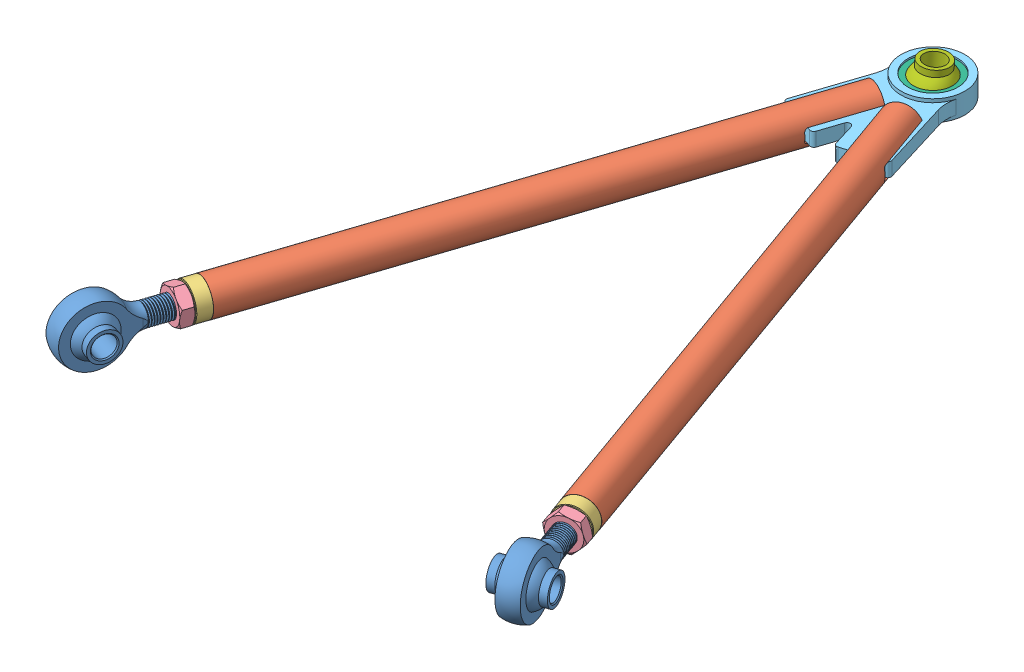
SolidWorks assembly SP-AB- Front Upper A-Arms, configuration Default. Lengths in mm.
Overall size (231.22 28.57 327.82).
12 component instances, 7 part files, 34 mates.
Components (placement in the parent):
- 6960T231_Super-Swivel Ball Joint Rod End-5: 6960T231_Super-Swivel Ball Joint Rod End [6960T231] at (-98.283 0 -18.0857) x (0 1 0) z (0.949383 0 0.314122) size (28.57 68.61 22.23)
- 6960T231_Super-Swivel Ball Joint Rod End-6: 6960T231_Super-Swivel Ball Joint Rod End [6960T231] at (90.2428 0 -17.9412) x (0 1 0) z (0.941797 0 -0.336181) size (28.57 68.61 22.23)
- SP-FR Upper A-Arm Tube-3: SP-FR Upper A-Arm Tube [Default] at (-14.3072 0 -271.889) x (0.949383 0 0.314122) z (-0.314122 0 0.949383) size (16 16 245.11)
- SP-10003-AD-Threaded Insert-3: SP-10003-AD-Threaded Insert [A-Arm] at (-88.3096 0 -48.2286) x (-0.327957 -0.93844 -0.108511) z (-0.314122 0 0.949383) size (15.88 15.88 15.88)
- SP-FR Upper A-Arm Tube-4: SP-FR Upper A-Arm Tube [Default] at (0.3699 0 -269.7167) x (0.941797 0 -0.336181) z (0.336181 0 0.941797) size (16 16 245.11)
- SP-10003-AD-Threaded Insert-4: SP-10003-AD-Threaded Insert [A-Arm] at (79.569 0 -47.8433) x (0.941797 0 -0.336181) z (0.336181 0 0.941797) size (15.88 15.88 15.88)
- FS-ZINC YELLOW THIN NUT G8 HX, 0.375x24-0.21875 (93839A815)-3: FS-ZINC YELLOW THIN NUT G8 HX, 0.375x24-0.21875 (93839A815) [Default] at (-94.169 0 -30.5197) x (0.938285 -0.152452 0.31045) z (0.144735 0.988311 0.047888) size (14.29 5.56 16.5)
- FS-ZINC YELLOW THIN NUT G8 HX, 0.375x24-0.21875 (93839A815)-4: FS-ZINC YELLOW THIN NUT G8 HX, 0.375x24-0.21875 (93839A815) [Default] at (85.8398 0 -30.2758) x (0.903878 0.280899 -0.322645) z (-0.26455 0.959737 0.094433) size (14.29 5.56 16.5)
- SP-Upper Apex Front-1: SP-Upper Apex Front [Default] at (-7.6268 0 -292.0759) x (0.949383 0 0.314122) z (0 1 0) size (51.11 64.07 9.53)
- FS-High Misalign Spherical Bearing, 0.375 (HAB-6TG)-1: FS-High Misalign Spherical Bearing, 0.375 (HAB-6TG) [Staked] at (-7.6268 -0.381 -292.0759) x (0.556958 0 0.830541) z (-0.830541 0 0.556958) size (23.01 22.43 23.01)
  - Race^FS-High Misalign Spherical Bearing, 0.375 (HAB-6TG)-1: Race^FS-High Misalign Spherical Bearing, 0.375 (HAB-6TG) [Default] at origin size (23.01 8.76 23.01) (virtual)
  - Ball^FS-High Misalign Spherical Bearing, 0.375 (HAB-6TG)-1: Ball^FS-High Misalign Spherical Bearing, 0.375 (HAB-6TG) [Default] x (0.998784 0.041144 -0.02715) z (0.025043 0.050892 0.99839) size (19.84 20.65 19.84) (virtual)
Mates (geometry in assembly coordinates):
- Concentric20: concentric aligned: circle of 6960T231_Super-Swivel Ball Joint Rod End-5
- Concentric21: concentric: cylinder of 6960T231_Super-Swivel Ball Joint Rod End-5 through (-114.0634 0 -3.2413) axis (0.949383 0 0.314122) radius 4.7625
- Concentric22: concentric anti-aligned: circle of 6960T231_Super-Swivel Ball Joint Rod End-6
- Concentric23: concentric: cylinder of 6960T231_Super-Swivel Ball Joint Rod End-6 through (86.9288 0 3.469) axis (0.941797 0 -0.336181) radius 4.7625
- Concentric24: concentric anti-aligned: cylinder of SP-FR Upper A-Arm Tube-3 through (-91.3016 0 -39.1858) axis (0.314122 0 -0.949383) radius 8.001
- Concentric25: concentric aligned: cylinder of SP-10003-AD-Threaded Insert-3 through (-93.2963 0 -33.1572) axis (-0.314122 0 0.949383) radius 4.7625
- Coincident42: coincident anti-aligned: circle of SP-FR Upper A-Arm Tube-3; plane of SP-10003-AD-Threaded Insert-3 through (-91.3016 0 -39.1858) normal (0.314122 0 -0.949383)
- Distance13: distance = 19.05 mm anti-aligned: plane of 6960T231_Super-Swivel Ball Joint Rod End-5 through (-87.3123 0 -51.2429) normal (0.314122 0 -0.949383); plane of SP-10003-AD-Threaded Insert-3 through (-93.2963 0 -33.1572) normal (-0.314122 0 0.949383)
- Concentric26: concentric aligned: cylinder of SP-FR Upper A-Arm Tube-4 through (82.7711 0 -38.8727) axis (-0.336181 0 -0.941797) radius 8.001
- Concentric27: concentric anti-aligned: cylinder of SP-10003-AD-Threaded Insert-4 through (84.9059 0 -32.8923) axis (0.336181 0 0.941797) radius 4.7625
- Coincident46: coincident anti-aligned: plane of SP-FR Upper A-Arm Tube-4 through (82.7711 0 -38.8727) normal (0.336181 0 0.941797); plane of SP-10003-AD-Threaded Insert-4 through (82.7711 0 -38.8727) normal (-0.336181 0 -0.941797)
- Distance14: distance = 19.05 mm anti-aligned: plane of SP-10003-AD-Threaded Insert-4 through (84.9059 0 -32.8923) normal (0.336181 0 0.941797); plane of 6960T231_Super-Swivel Ball Joint Rod End-6 through (78.5016 0 -50.8335) normal (-0.336181 0 -0.941797)
- Concentric28: concentric aligned: cylinder of SP-10004-AA-Outer Threaded Insert-2 through (0 0 -212.725) axis (0 0 1) radius 4.7625
- Distance15: distance = 212.725 mm aligned: plane of SP-10004-AA-Outer Threaded Insert-2 through (0 0 -212.725) normal (0 0 1)
- Concentric29: concentric anti-aligned: circle of 6960T231_Super-Swivel Ball Joint Rod End-7
- Parallel17: parallel aligned: unknown of 6960T231_Super-Swivel Ball Joint Rod End-7
- Concentric30: concentric: cylinder of 6960T231_Super-Swivel Ball Joint Rod End-7 through (-10.3187 0 -292.1) axis (1 0 0) radius 4.7625
- Concentric31: concentric anti-aligned: cylinder of SP-10003-AD-Threaded Insert-3 through (-93.2963 0 -33.1572) axis (0.314122 0 -0.949383) radius 7.9375; cylinder of FS-ZINC YELLOW THIN NUT G8 HX, 0.375x24-0.21875 (93839A815)-3 through (-93.2963 0 -33.1572) axis (-0.314122 0 0.949383) radius 4.7625
- Coincident54: coincident anti-aligned: plane of SP-10003-AD-Threaded Insert-3 through (-93.2963 0 -33.1572) normal (-0.314122 0 0.949383); plane of FS-ZINC YELLOW THIN NUT G8 HX, 0.375x24-0.21875 (93839A815)-3 through (-100.5961 -2.9872 -35.5725) normal (0.314122 0 -0.949383)
- Coincident55: coincident anti-aligned: plane of SP-10003-AD-Threaded Insert-4 through (84.9059 0 -32.8923) normal (0.336181 0 0.941797); plane of FS-ZINC YELLOW THIN NUT G8 HX, 0.375x24-0.21875 (93839A815)-4 through (79.5399 -5.9651 -30.9769) normal (-0.336181 0 -0.941797)
- Concentric32: concentric anti-aligned: cylinder of SP-10003-AD-Threaded Insert-4 through (84.9059 0 -32.8923) axis (-0.336181 0 -0.941797) radius 7.9375; cylinder of FS-ZINC YELLOW THIN NUT G8 HX, 0.375x24-0.21875 (93839A815)-4 through (84.9059 0 -32.8923) axis (0.336181 0 0.941797) radius 4.7625
- Coincident56: coincident anti-aligned: plane of SP-10004-AA-Outer Threaded Insert-2 through (0 0 -263.525) normal (0 0 -1); plane of FS-ZINC YELLOW THIN NUT G8 HX, 0.375x24-0.21875 (93839A815)-5 through (-7.1437 4.1244 -263.525) normal (0 0 1)
- Concentric34: concentric aligned: cylinder of SP-10004-AA-Outer Threaded Insert-2 through (0 0 -212.725) axis (0 0 -1) radius 7.9375; cylinder of FS-ZINC YELLOW THIN NUT G8 HX, 0.375x24-0.21875 (93839A815)-5 through (0 0 -263.525) axis (0 0 -1) radius 4.7625
- Perpendicular2: perpendicular: plane of 6960T231_Super-Swivel Ball Joint Rod End-6 through (105.7486 -14.2875 11.9216) normal (0.941797 0 -0.336181)
- Perpendicular5: perpendicular: plane of 6960T231_Super-Swivel Ball Joint Rod End-5 through (-113.0881 -14.2875 12.1306) normal (-0.949383 0 -0.314122)
- Parallel21: parallel aligned: line of SP-Upper Apex Front-1 through (-11.134 3.175 -263.7877) axis (-0.314122 0 0.949383)
- Concentric37: concentric: sphere of 6960T231_Super-Swivel Ball Joint Rod End-7; cylinder of SP-Upper Apex Front-1 through (0.0439 -4.7625 -292.0757) axis (0 1 0) radius 11.5062
- Concentric38: concentric anti-aligned: cylinder of SP-Upper Apex Front-1 through (-7.6268 -4.7625 -292.0759) axis (0 1 0) radius 11.5062; cylinder of FS-High Misalign Spherical Bearing, 0.375 (HAB-6TG)-1/Race^FS-High Misalign Spherical Bearing, 0.375 (HAB-6TG)-1 through (-7.6268 -13.081 -292.0759) axis (0 -1 0) radius 11.5062
- Coincident59: coincident anti-aligned: unknown of SP-Upper Apex Front-1; plane of FS-High Misalign Spherical Bearing, 0.375 (HAB-6TG)-1/Race^FS-High Misalign Spherical Bearing, 0.375 (HAB-6TG)-1 through (-12.5828 -4.7625 -299.4665) normal (0 -1 0)
- Concentric39: concentric: cylinder of FS-High Misalign Spherical Bearing, 0.375 (HAB-6TG)-1/Ball^FS-High Misalign Spherical Bearing, 0.375 (HAB-6TG)-1 through (-7.8517 -13.0538 -291.2758) axis (-0.017713 -0.997856 0.063001) radius 4.7625
- Parallel23: parallel aligned: plane of SP-Upper Apex Front-1 through (-7.6268 3.175 -292.0759) normal (0 1 0)
- Coincident68: coincident anti-aligned: plane of SP-FR Upper A-Arm Tube-3 through (-91.3016 0 -39.1858) normal (-0.314122 0 0.949383); plane of SP-10003-AD-Threaded Insert-3 through (-91.3016 0 -39.1858) normal (0.314122 0 -0.949383)
- Coincident71: coincident anti-aligned: plane of SP-FR Upper A-Arm Tube-3 through (287.3039 3.175 -172.095) normal (0 -1 0); plane of SP-Upper Apex Front-1 through (-7.6268 3.175 -292.0759) normal (0 1 0)
- Coincident72: coincident anti-aligned: plane of SP-FR Upper A-Arm Tube-4 through (299.5713 3.175 -376.5186) normal (0 -1 0); plane of SP-Upper Apex Front-1 through (-7.6268 3.175 -292.0759) normal (0 1 0)
